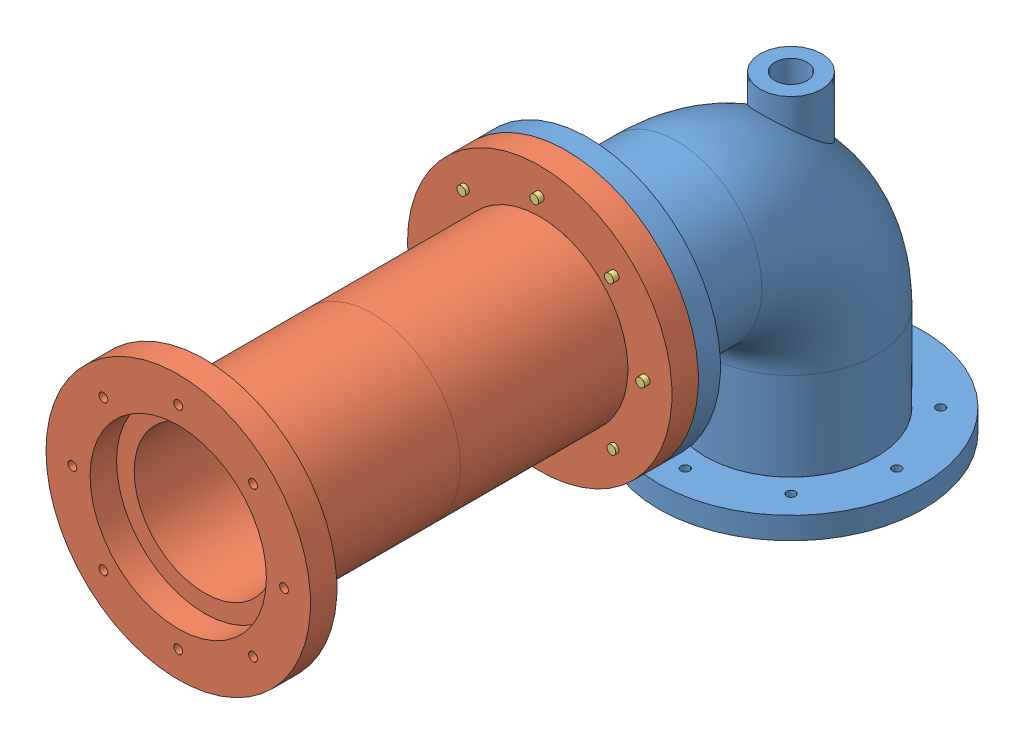
SolidWorks assembly boss and elbow, configuration Default. Lengths in mm.
Overall size (1500 2025 4225).
10 component instances, 3 part files, 10 mates.
Components (placement in the parent):
- boss-1: boss [Default] at (-1522.2504 1261.6846 -28.9299) size (1500 2025 2025)
- elbow-1: elbow [Default] at (-1522.2504 1261.6846 1696.0701) size (1500 1500 2200)
- bolt boss elbow-1: bolt boss elbow [Default] at (-1097.9863 1685.9486 472.5161) size (70 70 305)
- bolt boss elbow-2: bolt boss elbow [Default] at (-2122.2504 1261.6846 460.037) size (70 70 305)
- bolt boss elbow-3: bolt boss elbow [Default] at (-1522.2504 661.6846 461.171) size (70 70 305)
- bolt boss elbow-4: bolt boss elbow [Default] at (-922.2504 1261.6846 471.8513) size (70 70 305)
- bolt boss elbow-5: bolt boss elbow [Default] at (-1097.9863 837.4205 459.1313) size (70 70 305)
- bolt boss elbow-6: bolt boss elbow [Default] at (-1946.5145 1685.9486 461.5152) size (70 70 305)
- bolt boss elbow-7: bolt boss elbow [Default] at (-1946.5145 837.4205 460.5289) size (70 70 305)
- bolt boss elbow-8: bolt boss elbow [Default] at (-1522.2504 1861.6846 471.8452) size (70 70 305)
Mates (geometry in assembly coordinates):
- Coincident1: coincident anti-aligned: plane of boss-1 through (-1522.2504 1261.6846 596.0701) normal (0 0 1); plane of elbow-1 through (-1522.2504 1261.6846 596.0701) normal (0 0 -1)
- Concentric2: concentric aligned: circle of boss-1; circle of elbow-1
- Coincident4: coincident aligned: axis of boss-1 through (-1097.9863 1685.9486 596.0701) axis (0 0 -1); axis of bolt boss elbow-1 through (-1097.9863 1685.9486 777.5161) axis (0 0 -1)
- Coincident5: coincident anti-aligned: axis of elbow-1 through (-1522.2504 1861.6846 596.0701) axis (0 0 1); axis of bolt boss elbow-8 through (-1522.2504 1861.6846 776.8452) axis (0 0 -1)
- Coincident6: coincident aligned: axis of boss-1 through (-1946.5145 1685.9486 596.0701) axis (0 0 -1); axis of bolt boss elbow-6 through (-1946.5145 1685.9486 766.5152) axis (0 0 -1)
- Coincident7: coincident anti-aligned: axis of elbow-1 through (-2122.2504 1261.6846 596.0701) axis (0 0 1); axis of bolt boss elbow-2 through (-2122.2504 1261.6846 765.037) axis (0 0 -1)
- Coincident8: coincident anti-aligned: axis of elbow-1 through (-1946.5145 837.4205 596.0701) axis (0 0 1); axis of bolt boss elbow-7 through (-1946.5145 837.4205 765.5289) axis (0 0 -1)
- Coincident9: coincident aligned: axis of boss-1 through (-1522.2504 661.6846 596.0701) axis (0 0 -1); axis of bolt boss elbow-3 through (-1522.2504 661.6846 766.171) axis (0 0 -1)
- Coincident10: coincident aligned: axis of boss-1 through (-1097.9863 837.4205 596.0701) axis (0 0 -1); axis of bolt boss elbow-5 through (-1097.9863 837.4205 764.1313) axis (0 0 -1)
- Coincident11: coincident aligned: axis of boss-1 through (-922.2504 1261.6846 596.0701) axis (0 0 -1); axis of bolt boss elbow-4 through (-922.2504 1261.6846 776.8513) axis (0 0 -1)
